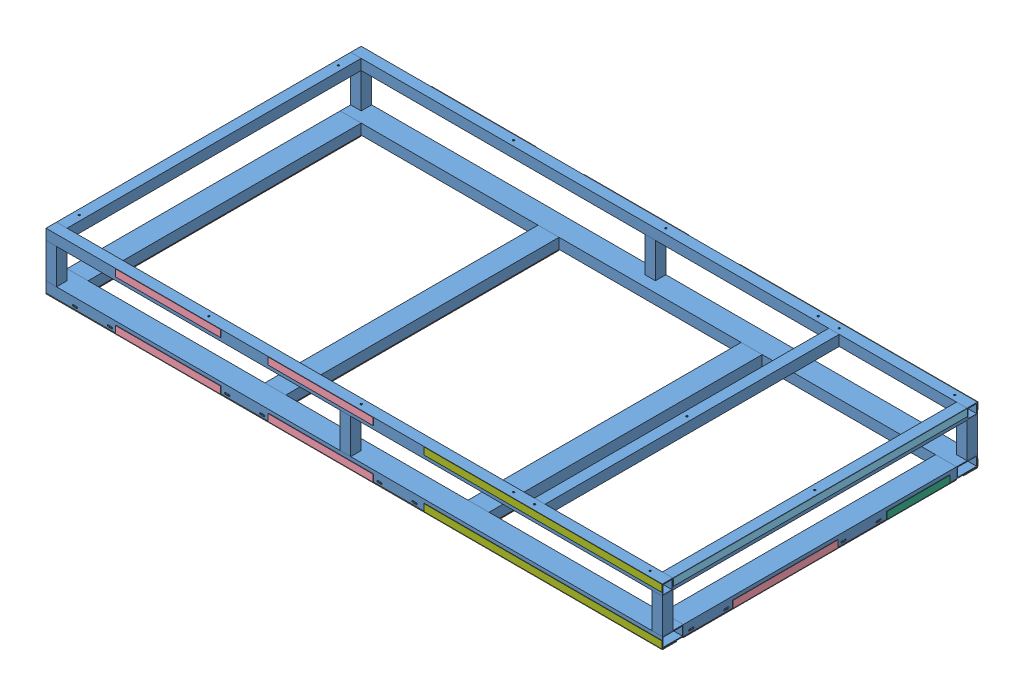
SolidWorks assembly GE-19071, configuration Default. Lengths in mm.
Overall size (2236.79 206.38 1146.17).
22 component instances, 7 part files, 45 mates.
Components (placement in the parent):
- GE-19071-1: GE-19071 [Default<As Machined>] at origin size (2235.2 203.2 1143)
- Hook_2_39-1: Hook_2_39 [Default] at (1092.2 -3.175 0) x (0 0 -1) z (1 0 0) size (990.6 3.17 50.8)
- Hook_2_88-1: Hook_2_88 [Default] at (0 -3.175 546.1) size (2235.2 3.17 50.8)
- Hook_2_39-2: Hook_2_39 [Default] at (387.35 -3.175 0) x (0 0 -1) z (1 0 0) size (990.6 3.17 50.8)
- Hook_2_39-3: Hook_2_39 [Default] at (-349.25 -3.175 0) x (0 0 -1) z (1 0 0) size (990.6 3.17 50.8)
- Hook_2_39-4: Hook_2_39 [Default] at (-1066.8 -3.175 0) x (0 0 -1) z (1 0 0) size (990.6 3.17 50.8)
- Hook_2_88-3: Hook_2_88 [Default] at (0 -3.175 -546.1) x (-1 0 0) z (0 0 -1) size (2235.2 3.17 50.8)
- Hook_1_15-1: Hook_1_15 [Default] at (1119.1875 0 -63.5) x (0 0 1) z (0 -1 0) size (381 1.59 25.4)
- Hook_1_42-1: Hook_1_42 [Default] at (1119.1875 203.2 533.4) x (0 0 -1) z (0 1 0) size (1066.8 1.59 25.4)
- Hook_1_9-1: Hook_1_9 [Default] at (1119.1875 0 -469.9) x (0 0 1) z (0 -1 0) size (228.6 1.59 25.4)
- Hook_1_15-2: Hook_1_15 [Default] at (-311.15 25.4 573.0875) x (1 0 0) z (0 1 0) size (381 1.59 25.4)
- Hook_1_34-1: Hook_1_34 [Default] at (254 25.4 573.0875) x (1 0 0) z (0 1 0) size (863.6 1.59 25.4)
- Hook_1_15-3: Hook_1_15 [Default] at (-863.6 25.4 573.0875) x (1 0 0) z (0 1 0) size (381 1.59 25.4)
- Hook_1_15-7: Hook_1_15 [Default] at (-863.6 0 -573.0875) x (1 0 0) z (0 -1 0) size (381 1.59 25.4)
- Hook_1_15-8: Hook_1_15 [Default] at (-311.15 0 -573.0875) x (1 0 0) z (0 -1 0) size (381 1.59 25.4)
- Hook_1_34-2: Hook_1_34 [Default] at (254 0 -573.0875) x (1 0 0) z (0 -1 0) size (863.6 1.59 25.4)
- Hook_1_15-10: Hook_1_15 [Default] at (-482.6 177.8 573.0875) x (-1 0 0) z (0 -1 0) size (381 1.59 25.4)
- Hook_1_15-12: Hook_1_15 [Default] at (69.85 177.8 573.0875) x (-1 0 0) z (0 -1 0) size (381 1.59 25.4)
- Hook_1_34-3: Hook_1_34 [Default] at (1117.6 177.8 573.0875) x (-1 0 0) z (0 -1 0) size (863.6 1.59 25.4)
- Hook_1_15-14: Hook_1_15 [Default] at (-482.6 203.2 -573.0875) x (-1 0 0) z (0 1 0) size (381 1.59 25.4)
- Hook_1_15-15: Hook_1_15 [Default] at (69.85 203.2 -573.0875) x (-1 0 0) z (0 1 0) size (381 1.59 25.4)
- Hook_1_34-6: Hook_1_34 [Default] at (1117.6 203.2 -573.0875) x (-1 0 0) z (0 1 0) size (863.6 1.59 25.4)
Mates (geometry in assembly coordinates):
- Coincident1: coincident: plane of GE-19071-1 through (-1117.6 0 571.5) normal (0 -1 0); plane of Hook_2_88-1 through (0 0 546.1) normal (0 1 0)
- Coincident2: coincident: plane of GE-19071-1 through (-1117.6 0 571.5) normal (0 0 1); plane of Hook_2_88-1 through (1117.6 0 571.5) normal (0 0 1)
- Coincident3: coincident: plane of GE-19071-1 through (1117.6 38.1 571.5) normal (1 0 0); plane of Hook_2_88-1 through (1117.6 0 571.5) normal (1 0 0)
- Coincident4: coincident: plane of GE-19071-1 through (1117.6 0 571.5) normal (0 -1 0); plane of Hook_2_39-1 through (1092.2 0 0) normal (0 1 0)
- Coincident5: coincident: plane of GE-19071-1 through (1117.6 0 571.5) normal (1 0 0); plane of Hook_2_39-1 through (1117.6 0 -495.3) normal (1 0 0)
- Coincident6: coincident: plane of Hook_2_39-1 through (1117.6 0 495.3) normal (0 0 1); plane of GE-19071-1 through (-1117.6 0 495.3) normal (0 0 -1)
- Coincident7: coincident: plane of GE-19071-1 through (1117.6 0 571.5) normal (0 -1 0); plane of Hook_2_39-2 through (387.35 0 0) normal (0 1 0)
- Coincident8: coincident: plane of GE-19071-1 through (412.75 0 495.3) normal (1 0 0); plane of Hook_2_39-2 through (412.75 0 -495.3) normal (1 0 0)
- Coincident9: coincident: plane of GE-19071-1 through (-1117.6 0 495.3) normal (0 0 -1); plane of Hook_2_39-2 through (412.75 0 495.3) normal (0 0 1)
- Coincident10: coincident: plane of GE-19071-1 through (1117.6 0 571.5) normal (0 -1 0); plane of Hook_2_39-3 through (-349.25 0 0) normal (0 1 0)
- Coincident11: coincident: plane of GE-19071-1 through (-1117.6 0 495.3) normal (0 0 -1); plane of Hook_2_39-3 through (-323.85 0 495.3) normal (0 0 1)
- Coincident12: coincident: plane of GE-19071-1 through (-323.85 0 495.3) normal (1 0 0); plane of Hook_2_39-3 through (-323.85 0 -495.3) normal (1 0 0)
- Coincident13: coincident: plane of GE-19071-1 through (1117.6 0 571.5) normal (0 -1 0); plane of Hook_2_39-4 through (-1066.8 0 0) normal (0 1 0)
- Coincident14: coincident: plane of GE-19071-1 through (-1117.6 0 495.3) normal (0 0 -1); plane of Hook_2_39-4 through (-1041.4 0 495.3) normal (0 0 1)
- Coincident15: coincident: plane of GE-19071-1 through (-1041.4 0 -571.5) normal (1 0 0); plane of Hook_2_39-4 through (-1041.4 0 -495.3) normal (1 0 0)
- Coincident24: coincident: plane of GE-19071-1 through (1117.6 0 -571.5) normal (0 -1 0); plane of Hook_2_88-3 through (0 0 -546.1) normal (0 1 0)
- Coincident25: coincident: plane of GE-19071-1 through (1117.6 0 -571.5) normal (0 0 -1); plane of Hook_2_88-3 through (-1117.6 0 -571.5) normal (0 0 -1)
- Coincident26: coincident: plane of GE-19071-1 through (-1117.6 38.1 -571.5) normal (-1 0 0); plane of Hook_2_88-3 through (-1117.6 0 -571.5) normal (-1 0 0)
- Coincident27: coincident: plane of GE-19071-1 through (1117.6 0 571.5) normal (1 0 0); plane of Hook_1_9-1 through (1117.6 0 -469.9) normal (-1 0 0)
- Coincident28: coincident: plane of GE-19071-1 through (1117.6 0 571.5) normal (0 -1 0); plane of Hook_1_9-1 through (1117.6 0 -469.9) normal (0 -1 0)
- Coincident29: coincident: plane of GE-19071-1 through (1117.6 0 571.5) normal (1 0 0); plane of Hook_1_15-1 through (1117.6 0 -63.5) normal (-1 0 0)
- Coincident30: coincident: plane of GE-19071-1 through (1117.6 0 571.5) normal (0 -1 0); plane of Hook_1_15-1 through (1117.6 0 -63.5) normal (0 -1 0)
- Coincident31: coincident: plane of GE-19071-1 through (1117.6 165.1 -571.5) normal (1 0 0); plane of Hook_1_42-1 through (1117.6 203.2 533.4) normal (-1 0 0)
- Coincident32: coincident: plane of GE-19071-1 through (1117.6 203.2 -571.5) normal (0 1 0); plane of Hook_1_42-1 through (1117.6 203.2 533.4) normal (0 1 0)
- Coincident33: coincident: plane of GE-19071-1 through (1117.6 0 533.4) normal (0 0 -1); plane of Hook_1_42-1 through (1117.6 203.2 533.4) normal (0 0 1)
- Distance1: distance = 254 mm: line of GE-19071-1; line of Hook_1_15-1 through (1119.1875 0 317.5) axis (0 1 0)
- Distance2: distance = 101.6 mm: plane of Hook_1_9-1 through (1117.6 0 -469.9) normal (0 0 -1); plane of GE-19071-1 through (1117.6 0 -571.5) normal (0 0 -1)
- Coincident36: coincident: plane of GE-19071-1 through (-1117.6 0 571.5) normal (0 0 1); plane of Hook_1_34-1 through (254 25.4 571.5) normal (0 0 -1)
- Coincident38: coincident: plane of GE-19071-1 through (-1117.6 0 571.5) normal (0 -1 0); plane of Hook_1_34-1 through (254 0 571.5) normal (0 -1 0)
- Coincident40: coincident: plane of GE-19071-1 through (1117.6 0 571.5) normal (1 0 0); plane of Hook_1_34-1 through (1117.6 25.4 571.5) normal (1 0 0)
- Coincident41: coincident: plane of GE-19071-1 through (-1117.6 0 571.5) normal (0 0 1); plane of Hook_1_15-2 through (-311.15 25.4 571.5) normal (0 0 -1)
- Coincident42: coincident: plane of GE-19071-1 through (-1117.6 0 571.5) normal (0 -1 0); plane of Hook_1_15-2 through (-311.15 0 571.5) normal (0 -1 0)
- Distance3: distance = 806.45 mm: plane of Hook_1_15-2 through (-311.15 25.4 571.5) normal (-1 0 0); plane of GE-19071-1 through (-1117.6 0 571.5) normal (-1 0 0)
- Coincident43: coincident: plane of GE-19071-1 through (-1117.6 0 571.5) normal (0 0 1); plane of Hook_1_15-3 through (-863.6 25.4 571.5) normal (0 0 -1)
- Coincident44: coincident: plane of GE-19071-1 through (-1117.6 0 571.5) normal (0 -1 0); plane of Hook_1_15-3 through (-863.6 0 571.5) normal (0 -1 0)
- Distance5: distance = 254 mm: plane of Hook_1_15-3 through (-863.6 25.4 571.5) normal (-1 0 0); plane of GE-19071-1 through (-1117.6 0 571.5) normal (-1 0 0)
- Coincident47: coincident: plane of GE-19071-1 through (1117.6 165.1 571.5) normal (0 0 1); plane of Hook_1_15-10 through (-482.6 177.8 571.5) normal (0 0 -1)
- Coincident48: coincident: plane of GE-19071-1 through (1117.6 203.2 571.5) normal (0 1 0); plane of Hook_1_15-10 through (-482.6 203.2 571.5) normal (0 1 0)
- Coincident49: coincident: plane of GE-19071-1 through (1117.6 165.1 571.5) normal (0 0 1); plane of Hook_1_15-12 through (69.85 177.8 571.5) normal (0 0 -1)
- Coincident50: coincident: plane of GE-19071-1 through (1117.6 203.2 571.5) normal (0 1 0); plane of Hook_1_15-12 through (69.85 203.2 571.5) normal (0 1 0)
- Coincident51: coincident: plane of assembly; plane of assembly; plane of Hook_1_15-3 through (-863.6 25.4 571.5) normal (-1 0 0); plane of Hook_1_15-10 through (-863.6 177.8 571.5) normal (-1 0 0)
- Coincident52: coincident: plane of assembly; plane of assembly; plane of Hook_1_15-2 through (-311.15 25.4 571.5) normal (-1 0 0); plane of Hook_1_15-12 through (-311.15 177.8 571.5) normal (-1 0 0)
- Coincident53: coincident: plane of GE-19071-1 through (1117.6 165.1 571.5) normal (0 0 1); plane of Hook_1_34-3 through (1117.6 177.8 571.5) normal (0 0 -1)
- Coincident54: coincident: plane of GE-19071-1 through (1117.6 203.2 571.5) normal (0 1 0); plane of Hook_1_34-3 through (1117.6 203.2 571.5) normal (0 1 0)
- Coincident56: coincident: plane of assembly; plane of assembly; plane of Hook_1_34-1 through (254 25.4 571.5) normal (-1 0 0); plane of Hook_1_34-3 through (254 177.8 571.5) normal (-1 0 0)
